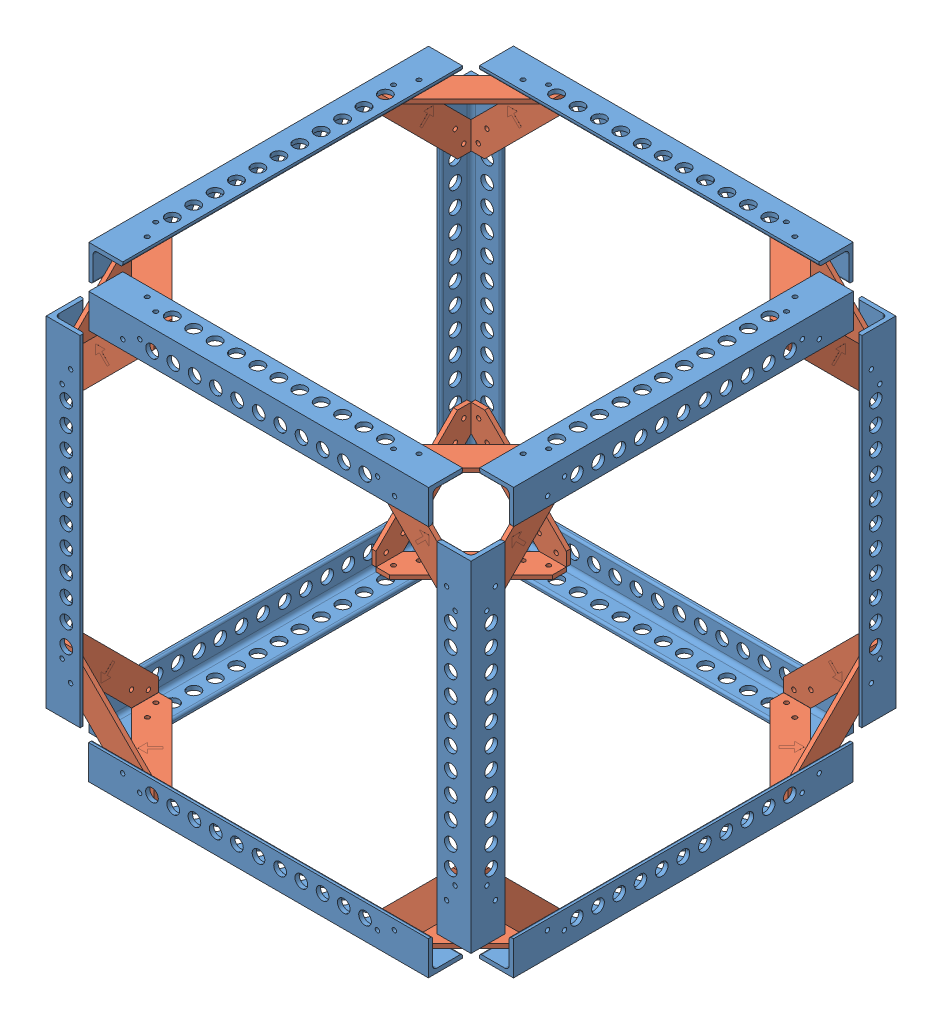
SolidWorks assembly Proof of Concept CAD 1, configuration Default. Lengths in mm.
Overall size (317.63 317.62 317.63).
38 component instances, 2 part files, 46 mates.
Components (placement in the parent):
- test assemby 1-1: test assemby 1 [Default] at (189.8318 11.2658 54.9643) size (317.51 25.4 317.63)
  - MOD Al L rod-4: MOD Al L rod [8982K401] at (158.011 130.5289 151.3983) size (25.4 25.4 254)
  - MOD Al L rod-5: MOD Al L rod [8982K401] at (11.9531 130.5289 5.2213) x (0 0 -1) z (1 0 0) size (25.4 25.4 254)
  - draft bracket-1: draft bracket [Default] at (164.361 121.0039 -1.0017) size (71.12 3.2 71.12)
  - MOD Al L rod-7: MOD Al L rod [8982K401] at (11.834 130.5289 297.4562) x (0 0 1) z (-1 0 0) size (25.4 25.4 254)
  - draft bracket-3: draft bracket [Default] at (164.234 121.0039 303.8062) x (0 0 1) z (-1 0 0) size (71.12 3.2 71.12)
  - MOD Al L rod-9: MOD Al L rod [8982K401] at (-134.0969 130.5289 151.2713) x (-1 0 0) z (0 0 -1) size (25.4 25.4 254)
  - draft bracket-6: draft bracket [Default] at (-140.4469 121.0039 -1.1287) x (0 0 -1) z (1 0 0) size (71.12 3.2 71.12)
  - draft bracket-7: draft bracket [Default] at (-140.4469 121.0039 303.6713) x (-1 0 0) z (0 0 -1) size (71.12 3.2 71.12)
- MOD Al L rod-1: MOD Al L rod [8982K401] at (55.6237 287.8447 352.4206) x (-1 0 0) z (0 -1 0) size (25.4 25.4 254)
- draft bracket-2: draft bracket [Default] at (49.2737 135.4447 361.9456) x (0 -1 0) z (1 0 0) size (71.12 3.2 71.12)
- draft bracket-3: draft bracket [Default] at (46.2099 135.5717 358.6357) x (0 0 1) z (0 1 0) size (71.12 3.2 71.12)
- draft bracket-4: draft bracket [Default] at (354.1928 135.4526 361.9456) x (1 0 0) z (0 1 0) size (71.12 3.2 71.12)
- draft bracket-5: draft bracket [Default] at (357.3678 135.4447 358.7706) x (0 -1 0) z (0 0 -1) size (71.12 3.2 71.12)
- MOD Al L rod-2: MOD Al L rod [8982K401] at (347.8428 287.8447 352.4206) x (0 0 1) z (0 -1 0) size (25.4 25.4 254)
- draft bracket-6: draft bracket [Default] at (49.3849 135.4447 50.6607) x (-1 0 0) z (0 1 0) size (71.12 3.2 71.12)
- draft bracket-7: draft bracket [Default] at (46.2099 135.4447 53.8357) x (0 -1 0) z (0 0 1) size (71.12 3.2 71.12)
- MOD Al L rod-3: MOD Al L rod [8982K401] at (55.7349 287.8447 60.1857) x (0 0 -1) z (0 -1 0) size (25.4 25.4 254)
- draft bracket-10: draft bracket [Default] at (357.3678 135.4447 53.8357) x (0 0 -1) z (0 1 0) size (71.12 3.2 71.12)
- draft bracket-11: draft bracket [Default] at (354.1928 135.4447 50.6607) x (0 -1 0) z (-1 0 0) size (71.12 3.2 71.12)
- MOD Al L rod-5: MOD Al L rod [8982K401] at (347.8428 287.8447 60.1857) x (1 0 0) z (0 -1 0) size (25.4 25.4 254)
- test assemby 1-2: test assemby 1 [Default] at (189.8397 564.5428 357.6419) x (1 0 0) z (0 0 -1) size (317.51 25.4 317.63)
  - MOD Al L rod-4: MOD Al L rod [8982K401] at (158.011 130.5289 151.3983) size (25.4 25.4 254)
  - MOD Al L rod-5: MOD Al L rod [8982K401] at (11.9531 130.5289 5.2213) x (0 0 -1) z (1 0 0) size (25.4 25.4 254)
  - draft bracket-1: draft bracket [Default] at (164.361 121.0039 -1.0017) size (71.12 3.2 71.12)
  - MOD Al L rod-7: MOD Al L rod [8982K401] at (11.834 130.5289 297.4562) x (0 0 1) z (-1 0 0) size (25.4 25.4 254)
  - draft bracket-3: draft bracket [Default] at (164.234 121.0039 303.8062) x (0 0 1) z (-1 0 0) size (71.12 3.2 71.12)
  - MOD Al L rod-9: MOD Al L rod [8982K401] at (-134.0969 130.5289 151.2713) x (-1 0 0) z (0 0 -1) size (25.4 25.4 254)
  - draft bracket-6: draft bracket [Default] at (-140.4469 121.0039 -1.1287) x (0 0 -1) z (1 0 0) size (71.12 3.2 71.12)
  - draft bracket-7: draft bracket [Default] at (-140.4469 121.0039 303.6713) x (-1 0 0) z (0 0 -1) size (71.12 3.2 71.12)
- draft bracket-13: draft bracket [Default] at (354.1928 440.2368 358.7706) x (1 0 0) z (0 -1 0) size (71.12 3.2 71.12)
- draft bracket-14: draft bracket [Default] at (354.1928 440.2526 358.6436) x (0 1 0) z (0 0 -1) size (71.12 3.2 71.12)
- draft bracket-15: draft bracket [Default] at (49.2737 440.2368 358.7706) x (0 0 1) z (0 -1 0) size (71.12 3.2 71.12)
- draft bracket-16: draft bracket [Default] at (49.2737 440.3638 358.7706) x (0 1 0) z (1 0 0) size (71.12 3.2 71.12)
- draft bracket-17: draft bracket [Default] at (49.2816 440.3638 50.6607) x (0 1 0) z (1 0 0) size (71.12 3.2 71.12)
- draft bracket-18: draft bracket [Default] at (354.1928 440.3638 53.8357) x (0 1 0) z (-1 0 0) size (71.12 3.2 71.12)
- draft bracket-19: draft bracket [Default] at (46.2099 440.2447 53.8357) x (0 0 -1) z (0 -1 0) size (71.12 3.2 71.12)
- draft bracket-20: draft bracket [Default] at (354.1928 440.2368 53.8357) x (0 0 -1) z (0 -1 0) size (71.12 3.2 71.12)
Mates (geometry in assembly coordinates):
- Coincident1: coincident aligned: circle of test assemby 1-1/MOD Al L rod-7; circle of draft bracket-2
- Coincident3: coincident aligned: line of test assemby 1-1/MOD Al L rod-7 through (74.6658 135.4447 361.9456) axis (1 0 0); line of draft bracket-2 through (100.0737 135.4447 361.9456) axis (1 0 0)
- Coincident4: coincident anti-aligned: circle of MOD Al L rod-1; circle of draft bracket-2
- Coincident6: coincident aligned: line of MOD Al L rod-1 through (49.2737 160.8447 361.9456) axis (0 1 0); line of draft bracket-2 through (49.2737 186.2447 361.9456) axis (0 1 0)
- Coincident7: coincident aligned: circle of test assemby 1-1/MOD Al L rod-9; circle of draft bracket-3
- Parallel1: parallel aligned: line of MOD Al L rod-1 through (46.0987 160.8447 358.7706) axis (0 1 0); line of draft bracket-3 through (46.2099 186.3717 358.6357) axis (0 1 0)
- Coincident13: coincident anti-aligned: circle of draft bracket-5; circle of MOD Al L rod-2
- Coincident14: coincident aligned: line of draft bracket-5 through (357.3678 186.2447 358.7706) axis (0 1 0); line of MOD Al L rod-2 through (357.3678 160.8447 358.7706) axis (0 1 0)
- Parallel2: parallel aligned: line of draft bracket-4 through (354.1928 186.2526 361.9456) axis (0 1 0); line of MOD Al L rod-2 through (354.1928 160.8447 361.9456) axis (0 1 0)
- Coincident15: coincident aligned: circle of draft bracket-4; circle of MOD Al L rod-2
- Coincident16: coincident aligned: line of test assemby 1-1/MOD Al L rod-4 through (357.3678 135.4447 333.3627) axis (0 0 -1); line of draft bracket-5 through (357.3678 135.4447 307.9706) axis (0 0 -1)
- Coincident17: coincident: circle of test assemby 1-1/MOD Al L rod-7; circle of draft bracket-4
- Parallel4: parallel anti-aligned: line of test assemby 1-1/MOD Al L rod-7 through (74.6658 135.4447 361.9456) axis (1 0 0); line of draft bracket-4 through (303.3928 135.4526 361.9456) axis (-1 0 0)
- Coincident19: coincident anti-aligned: circle of draft bracket-7; circle of MOD Al L rod-3
- Coincident20: coincident aligned: line of draft bracket-7 through (46.2099 186.2447 53.8357) axis (0 1 0); line of MOD Al L rod-3 through (46.2099 160.8447 53.8357) axis (0 1 0)
- Coincident21: coincident aligned: line of draft bracket-6 through (49.3849 186.2447 50.6607) axis (0 1 0); line of MOD Al L rod-3 through (49.3849 160.8447 50.6607) axis (0 1 0)
- Coincident23: coincident aligned: circle of draft bracket-6; circle of MOD Al L rod-3
- Coincident32: coincident anti-aligned: line of test assemby 1-1/MOD Al L rod-5 through (328.7849 135.4447 50.6607) axis (-1 0 0); line of draft bracket-6 through (100.1849 135.4447 50.6607) axis (1 0 0)
- Coincident33: coincident aligned: circle of test assemby 1-1/MOD Al L rod-9; circle of draft bracket-7
- Coincident34: coincident anti-aligned: circle of draft bracket-9; circle of MOD Al L rod-4
- Coincident35: coincident aligned: line of draft bracket-9 through (1439.6661 1201.1399 56.0831) axis (0 1 0); line of MOD Al L rod-4 through (1439.6661 1183.3599 56.0831) axis (0 1 0)
- Coincident36: coincident aligned: line of draft bracket-11 through (354.1928 186.2447 50.6607) axis (0 1 0); line of MOD Al L rod-5 through (354.1928 160.8447 50.6607) axis (0 1 0)
- Coincident37: coincident anti-aligned: circle of draft bracket-11; circle of MOD Al L rod-5
- Coincident38: coincident aligned: circle of draft bracket-10; circle of MOD Al L rod-5
- Coincident39: coincident aligned: line of draft bracket-10 through (357.3678 186.2447 53.8357) axis (0 1 0); line of MOD Al L rod-5 through (357.3678 160.8447 53.8357) axis (0 1 0)
- Coincident40: coincident anti-aligned: line of test assemby 1-1/MOD Al L rod-4 through (357.3678 135.4447 333.3627) axis (0 0 -1); line of draft bracket-10 through (357.3678 135.4447 104.6357) axis (0 0 1)
- Coincident41: coincident aligned: line of test assemby 1-1/MOD Al L rod-5 through (328.7849 135.4447 50.6607) axis (-1 0 0); line of draft bracket-11 through (303.3928 135.4447 50.6607) axis (-1 0 0)
- Coincident44: coincident anti-aligned: circle of MOD Al L rod-2; circle of draft bracket-13
- Coincident45: coincident anti-aligned: circle of test assemby 1-2/MOD Al L rod-5; circle of draft bracket-13
- Coincident46: coincident anti-aligned: line of MOD Al L rod-2 through (354.1928 160.8447 361.9456) axis (0 1 0); line of draft bracket-13 through (354.1928 389.4368 361.9456) axis (0 -1 0)
- Parallel5: parallel aligned: line of test assemby 1-2/MOD Al L rod-5 through (328.7928 440.3638 361.9456) axis (-1 0 0); line of draft bracket-13 through (303.3928 440.2368 361.9456) axis (-1 0 0)
- Coincident47: coincident anti-aligned: circle of MOD Al L rod-2; circle of draft bracket-14
- Parallel6: parallel anti-aligned: line of test assemby 1-2/MOD Al L rod-4 through (357.3757 440.3638 79.2436) axis (0 0 1); line of draft bracket-14 through (357.3678 440.2526 307.8436) axis (0 0 -1)
- Coincident52: coincident anti-aligned: line of test assemby 1-2/MOD Al L rod-5 through (328.7928 440.3638 361.9456) axis (-1 0 0); line of draft bracket-16 through (100.0737 440.3638 361.9456) axis (1 0 0)
- Coincident53: coincident anti-aligned: line of MOD Al L rod-1 through (49.2737 160.8447 361.9456) axis (0 1 0); line of draft bracket-16 through (49.2737 389.5638 361.9456) axis (0 -1 0)
- Coincident59: coincident aligned: line of test assemby 1-2/MOD Al L rod-9 through (46.2178 440.3638 333.3706) axis (0 0 -1); line of draft bracket-15 through (46.0987 440.2368 315.5906) axis (0 0 -1)
- Coincident62: coincident anti-aligned: circle of MOD Al L rod-1; circle of draft bracket-15
- Parallel12: parallel aligned: line of test assemby 1-2/MOD Al L rod-9 through (46.2178 440.3638 333.3706) axis (0 0 -1); line of draft bracket-15 through (46.0987 440.2368 307.9706) axis (0 0 -1)
- Coincident67: coincident aligned: circle of test assemby 1-2/MOD Al L rod-7; circle of draft bracket-17
- Parallel13: parallel anti-aligned: line of MOD Al L rod-3 through (49.3849 160.8447 50.6607) axis (0 1 0); line of draft bracket-17 through (49.2816 389.5638 50.6607) axis (0 -1 0)
- Coincident73: coincident anti-aligned: line of test assemby 1-2/MOD Al L rod-7 through (74.6737 440.3638 50.6607) axis (1 0 0); line of draft bracket-18 through (303.3928 440.3638 50.6607) axis (-1 0 0)
- Coincident74: coincident anti-aligned: line of MOD Al L rod-5 through (354.1928 160.8447 50.6607) axis (0 1 0); line of draft bracket-18 through (354.1928 389.5638 50.6607) axis (0 -1 0)
- Coincident79: coincident aligned: circle of MOD Al L rod-3; circle of draft bracket-19
- Parallel15: parallel anti-aligned: line of test assemby 1-2/MOD Al L rod-9 through (46.2178 440.3638 333.3706) axis (0 0 -1); line of draft bracket-19 through (46.2099 440.2447 104.6357) axis (0 0 1)
- Coincident83: coincident anti-aligned: circle of MOD Al L rod-5; circle of draft bracket-20
- Parallel16: parallel aligned: line of test assemby 1-2/MOD Al L rod-4 through (357.3757 440.3638 79.2436) axis (0 0 1); line of draft bracket-20 through (357.3678 440.2368 104.6357) axis (0 0 1)
